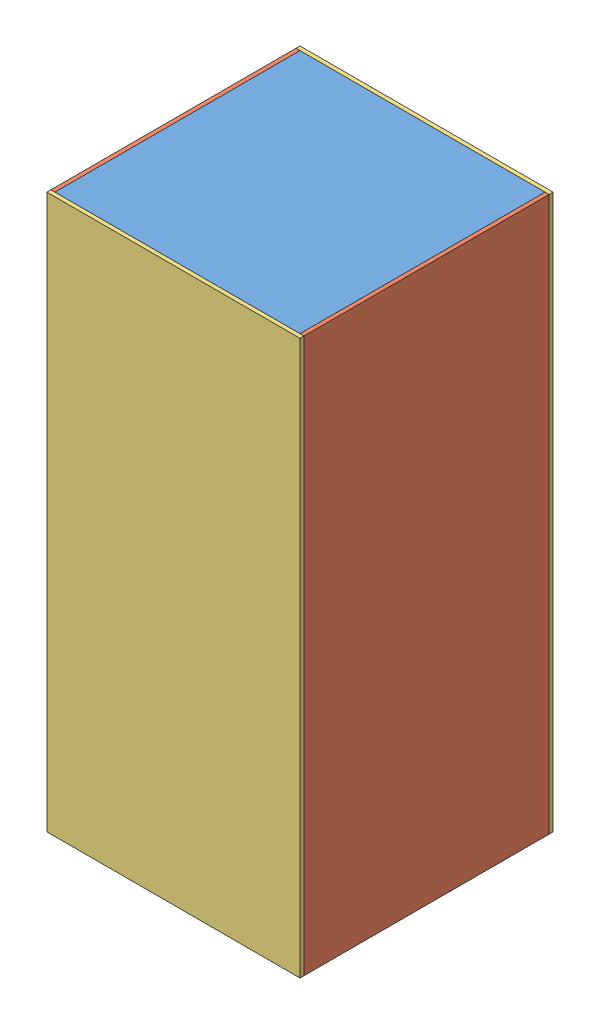
SolidWorks assembly 2U, configuration Default. Lengths in mm.
Overall size (103.25 368.65 103.25).
10 component instances, 4 part files, 29 mates.
Components (placement in the parent):
- TopAndBottom-1: TopAndBottom [Default] at (50.7636 57.9706 65.1859) size (100 1.63 100)
- LeftAndRight-1: LeftAndRight [Default] at (-0.862 170.9706 65.1859) size (1.63 226 100)
- FrontAndBack-1: FrontAndBack [Default] at (50.7636 170.9706 13.5603) size (103.25 226 1.63)
- LeftAndRight-3: LeftAndRight [Default] at (100.7636 170.9706 65.1859) size (1.63 226 100)
- FrontAndBack-3: FrontAndBack [Default] at (50.7636 170.9706 115.1859) size (103.25 226 1.63)
- Support Stock-1: Support Stock [Default] at (5.5261 170.9625 19.9484) size (9.91 368.65 9.91)
- Support Stock-2: Support Stock [Default] at (5.5261 170.9625 110.4234) size (9.91 368.65 9.91)
- Support Stock-3: Support Stock [Default] at (96.0011 170.9625 110.4234) size (9.91 368.65 9.91)
- Support Stock-4: Support Stock [Default] at (96.0011 170.9625 19.9484) size (9.91 368.65 9.91)
- TopAndBottom-2: TopAndBottom [Default] at (50.7636 282.345 65.1859) size (100 1.63 100)
Mates (geometry in assembly coordinates):
- Coincident1: coincident aligned: plane of TopAndBottom-1 through (50.7636 57.9706 65.1859) normal (0 -1 0); plane of LeftAndRight-1 through (0.7636 57.9706 115.1859) normal (0 -1 0)
- Coincident2: coincident anti-aligned: plane of TopAndBottom-1 through (0.7636 59.5962 15.1859) normal (-1 0 0); plane of LeftAndRight-1 through (0.7636 170.9706 65.1859) normal (1 0 0)
- Coincident3: coincident aligned: plane of TopAndBottom-1 through (0.7636 59.5962 115.1859) normal (0 0 1); plane of LeftAndRight-1 through (0.7636 283.9706 115.1859) normal (0 0 1)
- Coincident5: coincident aligned: plane of TopAndBottom-1 through (50.7636 57.9706 65.1859) normal (0 -1 0); plane of FrontAndBack-1 through (-0.862 57.9706 15.1859) normal (0 -1 0)
- Coincident6: coincident anti-aligned: plane of TopAndBottom-1 through (0.7636 59.5962 15.1859) normal (0 0 -1); plane of FrontAndBack-1 through (50.7636 170.9706 15.1859) normal (0 0 1)
- Coincident7: coincident aligned: plane of LeftAndRight-1 through (-0.862 170.9706 65.1859) normal (-1 0 0); plane of FrontAndBack-1 through (-0.862 283.9706 15.1859) normal (-1 0 0)
- Coincident8: coincident aligned: plane of TopAndBottom-1 through (50.7636 57.9706 65.1859) normal (0 -1 0); plane of LeftAndRight-3 through (102.3892 57.9706 115.1859) normal (0 -1 0)
- Coincident9: coincident anti-aligned: plane of TopAndBottom-1 through (100.7636 59.5962 15.1859) normal (1 0 0); plane of LeftAndRight-3 through (100.7636 170.9706 65.1859) normal (-1 0 0)
- Coincident10: coincident anti-aligned: plane of FrontAndBack-1 through (50.7636 170.9706 15.1859) normal (0 0 1); plane of LeftAndRight-3 through (102.3892 283.9706 15.1859) normal (0 0 -1)
- Coincident11: coincident anti-aligned: plane of LeftAndRight-3 through (102.3892 283.9706 115.1859) normal (0 0 1); plane of FrontAndBack-3 through (50.7636 170.9706 115.1859) normal (0 0 -1)
- Coincident12: coincident anti-aligned: plane of TopAndBottom-1 through (0.7636 59.5962 115.1859) normal (0 0 1); plane of FrontAndBack-3 through (50.7636 170.9706 115.1859) normal (0 0 -1)
- Coincident13: coincident aligned: plane of TopAndBottom-1 through (50.7636 57.9706 65.1859) normal (0 -1 0); plane of FrontAndBack-3 through (-0.862 57.9706 116.8115) normal (0 -1 0)
- Coincident14: coincident aligned: plane of LeftAndRight-3 through (102.3892 170.9706 65.1859) normal (1 0 0); plane of FrontAndBack-3 through (102.3892 283.9706 116.8115) normal (1 0 0)
- Coincident15: coincident aligned: plane of Support Stock-2 through (5.5261 59.5962 110.4234) normal (0 -1 0); plane of Support Stock-3 through (96.0011 59.5962 110.4234) normal (0 -1 0)
- Coincident16: coincident aligned: plane of Support Stock-3 through (96.0011 59.5962 110.4234) normal (0 -1 0); plane of Support Stock-4 through (96.0011 59.5962 19.9484) normal (0 -1 0)
- Coincident17: coincident aligned: plane of Support Stock-1 through (5.5261 59.5962 19.9484) normal (0 -1 0); plane of Support Stock-4 through (96.0011 59.5962 19.9484) normal (0 -1 0)
- Coincident18: coincident anti-aligned: plane of TopAndBottom-1 through (50.7636 59.5962 65.1859) normal (0 1 0); plane of Support Stock-3 through (96.0011 59.5962 110.4234) normal (0 -1 0)
- Coincident19: coincident anti-aligned: plane of LeftAndRight-3 through (100.7636 170.9706 65.1859) normal (-1 0 0); plane of Support Stock-3 through (100.7636 282.3288 105.6609) normal (1 0 0)
- Coincident20: coincident anti-aligned: plane of FrontAndBack-3 through (50.7636 170.9706 115.1859) normal (0 0 -1); plane of Support Stock-3 through (91.2386 282.3288 115.1859) normal (0 0 1)
- Coincident21: coincident anti-aligned: plane of LeftAndRight-3 through (100.7636 170.9706 65.1859) normal (-1 0 0); plane of Support Stock-4 through (100.7636 282.3288 15.1859) normal (1 0 0)
- Coincident22: coincident anti-aligned: plane of FrontAndBack-1 through (50.7636 170.9706 15.1859) normal (0 0 1); plane of Support Stock-4 through (91.2386 282.3288 15.1859) normal (0 0 -1)
- Coincident23: coincident anti-aligned: plane of FrontAndBack-1 through (50.7636 170.9706 15.1859) normal (0 0 1); plane of Support Stock-1 through (0.7636 282.3288 15.1859) normal (0 0 -1)
- Coincident24: coincident anti-aligned: plane of LeftAndRight-1 through (0.7636 170.9706 65.1859) normal (1 0 0); plane of Support Stock-1 through (0.7636 282.3288 15.1859) normal (-1 0 0)
- Coincident25: coincident anti-aligned: plane of LeftAndRight-1 through (0.7636 170.9706 65.1859) normal (1 0 0); plane of Support Stock-2 through (0.7636 282.3288 105.6609) normal (-1 0 0)
- Coincident26: coincident anti-aligned: plane of FrontAndBack-3 through (50.7636 170.9706 115.1859) normal (0 0 -1); plane of Support Stock-2 through (0.7636 282.3288 115.1859) normal (0 0 1)
- Coincident28: coincident anti-aligned: plane of FrontAndBack-1 through (50.7636 170.9706 15.1859) normal (0 0 1); plane of TopAndBottom-2 through (0.7636 283.9706 15.1859) normal (0 0 -1)
- Coincident30: coincident: line of LeftAndRight-3 through (102.3892 283.9706 15.1859) axis (0 0 1); plane of TopAndBottom-2 through (50.7636 283.9706 65.1859) normal (0 1 0)
- Parallel1: parallel anti-aligned: plane of TopAndBottom-2 through (100.7636 283.9706 15.1859) normal (1 0 0); plane of LeftAndRight-3 through (100.7636 170.9706 65.1859) normal (-1 0 0)
- Coincident33: coincident anti-aligned: plane of LeftAndRight-3 through (100.7636 170.9706 65.1859) normal (-1 0 0); plane of TopAndBottom-2 through (100.7636 283.9706 15.1859) normal (1 0 0)
